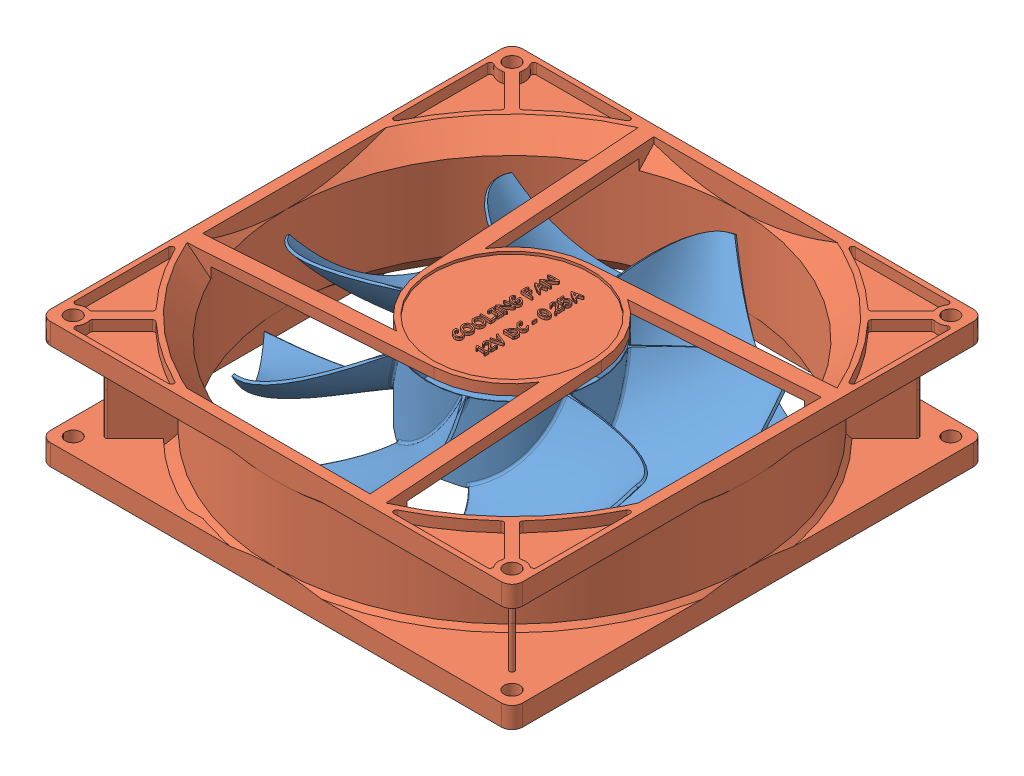
SolidWorks assembly ASM, configuration Default. Lengths in mm.
Overall size (99.64 27.52 98.92).
2 component instances, 2 part files, 2 mates.
Components (placement in the parent):
- canhquat-1: canhquat [Default] at (-64.2015 26.2513 40.0813) x (-0.373581 0 -0.927598) z (-0.927598 0 0.373581) size (75.64 15.06 76.95)
- vo-1: vo [Default] at (-64.2015 17.2513 40.0813) size (90 27.52 90.5)
Mates (geometry in assembly coordinates):
- Concentric1: concentric aligned: circle of canh quạt-1; circle of vo-1
- Distance1: distance = 6 mm aligned: plane of canh quạt-1 through (-64.2015 11.2513 40.0813) normal (0 -1 0); plane of vo-1 through (-64.2015 5.2513 40.0813) normal (0 -1 0)
